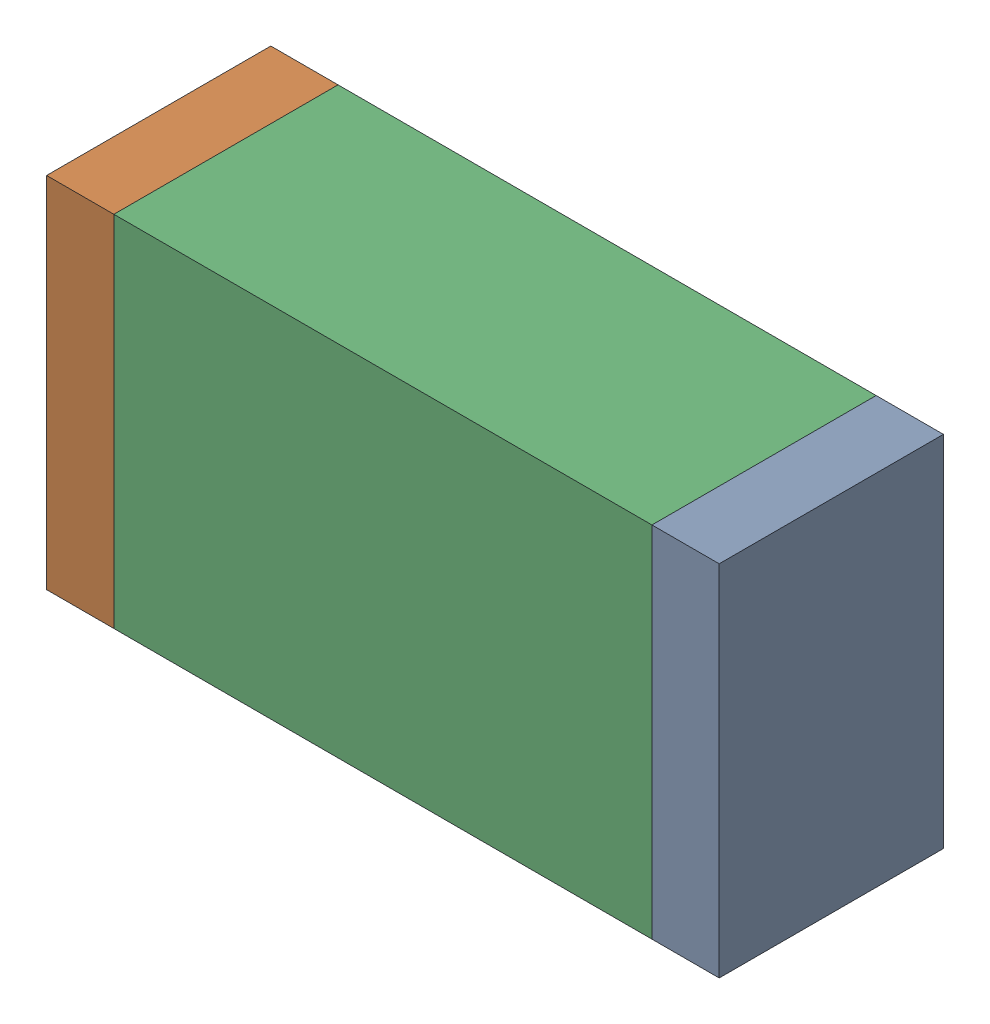
SolidWorks assembly D5, configuration Default. Lengths in mm.
Overall size (1.5 0.8 0.5).
6 component instances, 2 part files, 0 mates.
Components (placement in the parent):
- 836752496-1: 836752496 [Default] at (127.725 13.5 0) size (0.15 0.8 0.5)
  - Extruded_2-1: Extruded_2 [Default] at origin size (0.15 0.8 0.5)
- 836752496-2: 836752496 [Default] at (126.375 13.5 0) size (0.15 0.8 0.5)
  - Extruded_2-1: Extruded_2 [Default] at origin size (0.15 0.8 0.5)
- 836752368-1: 836752368 [Default] at (127.05 13.5 0) size (1.2 0.8 0.5)
  - Extruded-1: Extruded [Default] at origin size (1.2 0.8 0.5)
